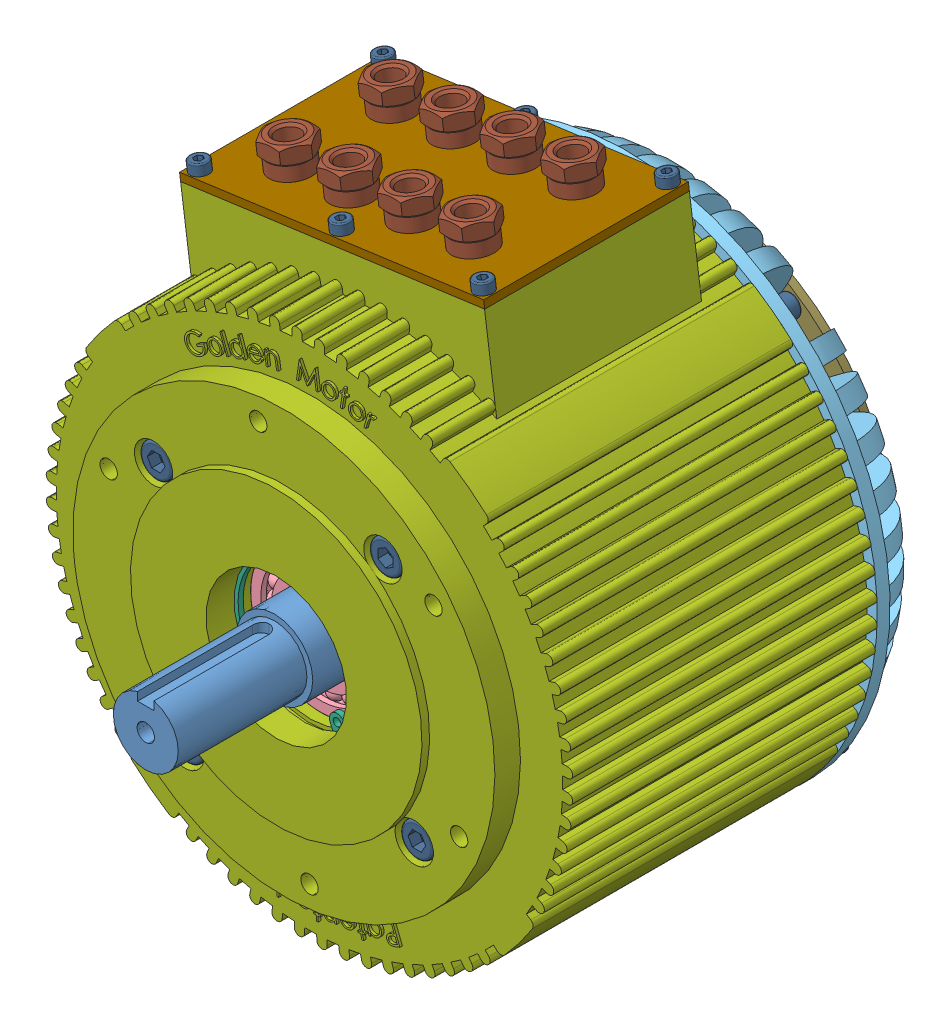
SolidWorks assembly (外形图）风冷图, configuration 默认. Lengths in mm.
Overall size (233.48 249.83 219).
48 component instances, 13 part files, 43 mates.
Components (placement in the parent):
- 轴-1: 轴 [默认] at (4.5506 0 -103.5) size (35 35 206.3)
- Hexagon socket button head screws GB-1: Hexagon socket button head screws GB [GB_SOCKET_TYPE7 M4X8-N] at (-6.919 -27.7209 -32.7) x (0 0 1) z (0.923728 0.383049 0) size (10.2 7.6 7.6)
- Hexagon socket button head screws GB-2: Hexagon socket button head screws GB [GB_SOCKET_TYPE7 M4X8-N] at (-6.9409 27.7118 -16.3) x (0 0 -1) z (1 0 0) size (10.2 7.6 7.6)
- Circlips for shaft--Type A large GB-1: Circlips for shaft--Type A large GB [GB_CONNECTING_PIECE_RING_RRA 30] at (4.3214 0.9013 -39.6) x (0.969151 0.246466 0) z (0 0 1) size (33.5 36.57 1.2)
- Deep groove ball bearings GB-1: Deep groove ball bearings GB [Rolling bearings 16006 GB 276-94] at (4.5506 0 30) x (0 0 1) z (0.923728 0.383049 0) size (9 55 55)
- Deep groove ball bearings GB-2: Deep groove ball bearings GB [Rolling bearings 6205 GB 276-94] at (4.5506 0 -72) x (0 0 1) z (-1 0 0) size (15 52 52)
- 盖-1: 盖 [默认] at (4.5506 0 -61) x (0.135368 -0.990795 0) z (0 0 -1) size (206 206 49.2)
- Circlips for holes--Type A GB-1: Circlips for holes--Type A GB [GB_CONNECTING_PIECE_RING_RRH 52] at (5.0102 -1.1085 -81.5) x (0.923728 0.383049 0) z (0 0 -1) size (56.2 54.06 2)
- 机壳-1: 机壳 [默认] at (4.5506 0 51.8) x (-0.990795 -0.135368 0) z (0 0 -1) size (206 217 132)
- 风页-1: 风页 [默认] at (4.5506 0 -82.4) x (0 0 1) z (-1 0 0) size (25.28 108.45 96.5)
- 出线板-1: 出线板 [默认] at (-6.2623 113.5818 -4.2972) x (0.990795 0.135368 0) z (-0.135368 0.990795 0) size (120 80 3)
- Hexagon socket head cap screws GB-1: Hexagon socket head cap screws GB [GB_FASTENER_SCREWS_HSHCS M5X16-N] at (-73.4886 59.2781 -90.2) x (0 0 1) z (-1 0 0) size (21 8.5 8.5)
- Hexagon socket head cap screws GB-2: Hexagon socket head cap screws GB [GB_FASTENER_SCREWS_HSHCS M8X16-N] at (43.2628 50.9643 -93.2) x (0 0 1) z (-1 0 0) size (24 13 13)
- Hexagon socket head cap screws GB-3: Hexagon socket head cap screws GB [GB_FASTENER_SCREWS_HSHCS M8X20-N] at (-46.4138 38.7122 47.8) x (0 0 -1) z (1 0 0) size (28 13 13)
- Prevailing torque type 1 with fine pitch GB-1: Prevailing torque type 1 with fine pitch GB [GB_HEXAGON_TYPE11 M10X1-N] at (-47.654 116.1578 -45.7) x (0.497865 0.068021 -0.864583) z (0.135368 -0.990795 0) size (18.48 16 11.9)
- Hexagon socket head cap screws GB-4: Hexagon socket head cap screws GB [GB_FASTENER_SCREWS_HSHCS M3X10-N] at (-4.9252 69.3557 -116.2) x (0 0 1) z (0.380828 0.924646 0) size (13 5.5 5.5)
- Circlips for shaft--Type A large GB-3: Circlips for shaft--Type A large GB [GB_CONNECTING_PIECE_RING_RRA 14] at (4.5506 0.47 -100.4) size (15.7 18.22 1)
- Hexagon socket head cap screws GB-5: Hexagon socket head cap screws GB [GB_FASTENER_SCREWS_HSHCS M8X20-N] at (43.2628 50.9643 47.8) x (0 0 -1) z (0 -1 0) size (28 13 13)
- Hexagon socket head cap screws GB-6: Hexagon socket head cap screws GB [GB_FASTENER_SCREWS_HSHCS M8X20-N] at (55.5149 -38.7122 47.8) x (0 0 -1) z (-1 0 0) size (28 13 13)
- Hexagon socket head cap screws GB-7: Hexagon socket head cap screws GB [GB_FASTENER_SCREWS_HSHCS M8X20-N] at (-34.1616 -50.9643 47.8) x (0 0 -1) z (0 1 0) size (28 13 13)
- Hexagon socket head cap screws GB-8: Hexagon socket head cap screws GB [GB_FASTENER_SCREWS_HSHCS M8X16-N] at (55.5149 -38.7122 -93.2) x (0 0 1) z (0 1 0) size (24 13 13)
- Hexagon socket head cap screws GB-9: Hexagon socket head cap screws GB [GB_FASTENER_SCREWS_HSHCS M8X16-N] at (-34.1616 -50.9643 -93.2) x (0 0 1) z (1 0 0) size (24 13 13)
- Hexagon socket head cap screws GB-10: Hexagon socket head cap screws GB [GB_FASTENER_SCREWS_HSHCS M8X16-N] at (-46.4138 38.7122 -93.2) x (0 0 1) z (0 -1 0) size (24 13 13)
- Hexagon socket head cap screws GB-11: Hexagon socket head cap screws GB [GB_FASTENER_SCREWS_HSHCS M5X16-N] at (63.8287 78.0391 -90.2) x (0 0 1) z (0 1 0) size (21 8.5 8.5)
- Hexagon socket head cap screws GB-12: Hexagon socket head cap screws GB [GB_FASTENER_SCREWS_HSHCS M5X16-N] at (82.5897 -59.2781 -90.2) x (0 0 1) z (1 0 0) size (21 8.5 8.5)
- Hexagon socket head cap screws GB-13: Hexagon socket head cap screws GB [GB_FASTENER_SCREWS_HSHCS M5X16-N] at (-54.7275 -78.0391 -90.2) x (0 0 1) z (0 -1 0) size (21 8.5 8.5)
- Circlips for holes--Type A GB-2: Circlips for holes--Type A GB [GB_CONNECTING_PIECE_RING_RRH 55] at (4.5506 1.2 40.6) size (59.2 56.95 2)
- Prevailing torque type 1 with fine pitch GB-2: Prevailing torque type 1 with fine pitch GB [GB_HEXAGON_TYPE11 M10X1-N] at (-47.654 116.1578 -5.7) x (0.497865 0.068021 -0.864583) z (0.135368 -0.990795 0) size (18.48 16 11.9)
- Prevailing torque type 1 with fine pitch GB-3: Prevailing torque type 1 with fine pitch GB [GB_HEXAGON_TYPE11 M10X1-N] at (-23.8749 119.4066 -45.7) x (0.497865 0.068021 -0.864583) z (0.135368 -0.990795 0) size (18.48 16 11.9)
- Prevailing torque type 1 with fine pitch GB-4: Prevailing torque type 1 with fine pitch GB [GB_HEXAGON_TYPE11 M10X1-N] at (-23.8749 119.4066 -5.7) x (0.497865 0.068021 -0.864583) z (0.135368 -0.990795 0) size (18.48 16 11.9)
- Prevailing torque type 1 with fine pitch GB-5: Prevailing torque type 1 with fine pitch GB [GB_HEXAGON_TYPE11 M10X1-N] at (-0.0958 122.6554 -45.7) x (0.497865 0.068021 -0.864583) z (0.135368 -0.990795 0) size (18.48 16 11.9)
- Prevailing torque type 1 with fine pitch GB-6: Prevailing torque type 1 with fine pitch GB [GB_HEXAGON_TYPE11 M10X1-N] at (-0.0958 122.6554 -5.7) x (0.497865 0.068021 -0.864583) z (0.135368 -0.990795 0) size (18.48 16 11.9)
- Prevailing torque type 1 with fine pitch GB-7: Prevailing torque type 1 with fine pitch GB [GB_HEXAGON_TYPE11 M10X1-N] at (23.6833 125.9043 -45.7) x (0.497865 0.068021 -0.864583) z (0.135368 -0.990795 0) size (18.48 16 11.9)
- Prevailing torque type 1 with fine pitch GB-8: Prevailing torque type 1 with fine pitch GB [GB_HEXAGON_TYPE11 M10X1-N] at (23.6833 125.9043 -5.7) x (0.497865 0.068021 -0.864583) z (0.135368 -0.990795 0) size (18.48 16 11.9)
- Hexagon socket head cap screws GB-14: Hexagon socket head cap screws GB [GB_FASTENER_SCREWS_HSHCS M4X10-N] at (-67.3135 112.3056 10.3) x (0.135368 -0.990795 0) z (0 0 1) size (14 7 7)
- Hexagon socket head cap screws GB-15: Hexagon socket head cap screws GB [GB_FASTENER_SCREWS_HSHCS M4X10-N] at (-67.3135 112.3056 -61.7) x (0.135368 -0.990795 0) z (0 0 1) size (14 7 7)
- Hexagon socket head cap screws GB-16: Hexagon socket head cap screws GB [GB_FASTENER_SCREWS_HSHCS M4X10-N] at (-11.829 119.8862 10.3) x (0.135368 -0.990795 0) z (0 0 1) size (14 7 7)
- Hexagon socket head cap screws GB-17: Hexagon socket head cap screws GB [GB_FASTENER_SCREWS_HSHCS M4X10-N] at (-11.829 119.8862 -61.7) x (0.135368 -0.990795 0) z (0 0 1) size (14 7 7)
- Hexagon socket head cap screws GB-18: Hexagon socket head cap screws GB [GB_FASTENER_SCREWS_HSHCS M4X10-N] at (43.6556 127.4669 10.3) x (0.135368 -0.990795 0) z (0 0 1) size (14 7 7)
- Hexagon socket head cap screws GB-19: Hexagon socket head cap screws GB [GB_FASTENER_SCREWS_HSHCS M4X10-N] at (43.6556 127.4669 -61.7) x (0.135368 -0.990795 0) z (0 0 1) size (14 7 7)
- 风页盖板-1: 风页盖板 [默认] at (4.5506 0 -113.2) x (0.990795 0.135368 0) z (0 0 1) size (150 150 3)
- Hexagon socket head cap screws GB-20: Hexagon socket head cap screws GB [GB_FASTENER_SCREWS_HSHCS M3X10-N] at (-64.8051 -9.4758 -116.2) x (0 0 1) z (-0.924646 0.380828 0) size (13 5.5 5.5)
- Hexagon socket head cap screws GB-21: Hexagon socket head cap screws GB [GB_FASTENER_SCREWS_HSHCS M3X10-N] at (14.0264 -69.3557 -116.2) x (0 0 1) z (-0.380828 -0.924646 0) size (13 5.5 5.5)
- Hexagon socket head cap screws GB-22: Hexagon socket head cap screws GB [GB_FASTENER_SCREWS_HSHCS M3X10-N] at (73.9063 9.4758 -116.2) x (0 0 1) z (0.924646 -0.380828 0) size (13 5.5 5.5)
- 端子-1: 端子 [默认] at (-63.2107 -47.0601 -82.2) x (-0.923728 -0.383049 0) z (0 0 -1) size (12 12 4)
- 端子-2: 端子 [默认] at (-73.3509 27.1588 -82.2) x (-0.852847 0.522161 0) z (0 0 -1) size (12 12 4)
- 端子-3: 端子 [默认] at (-77.9307 1.7567 -82.2) x (-0.972462 0.233061 0) z (0 0 -1) size (12 12 4)
- 端子-4: 端子 [默认] at (-74.4366 -23.8174 -82.2) x (-0.996886 -0.078854 0) z (0 0 -1) size (12 12 4)
Mates (geometry in assembly coordinates):
- 同心8: concentric anti-aligned: circle of 轴-1; circle of Circlips for shaft--Type A large GB-1
- 重合6: coincident anti-aligned: circle of 轴-1; plane of Circlips for shaft--Type A large GB-1 through (4.5506 0 -40.8) normal (0 0 -1)
- 同心11: concentric anti-aligned: circle of 轴-1; circle of Deep groove ball bearings GB-2
- 重合10: coincident aligned: circle of 轴-1; plane of Deep groove ball bearings GB-2 through (4.5506 12.5 -64.5) normal (0 0 1)
- 同心12: concentric aligned: circle of 轴-1; circle of Deep groove ball bearings GB-1
- 重合11: coincident anti-aligned: plane of 轴-1 through (4.5506 0 25.5) normal (0 0 1); plane of Deep groove ball bearings GB-1 through (15.0844 -25.4025 25.5) normal (0 0 -1)
- 重合13: coincident aligned: plane of Deep groove ball bearings GB-2 through (4.5506 26 -79.5) normal (0 0 -1); circle of 盖-1
- 同心15: concentric aligned: circle of 轴-1; circle of Circlips for holes--Type A GB-1
- 重合14: coincident anti-aligned: plane of 盖-1 through (4.5506 0 -79.5) normal (0 0 -1); plane of Circlips for holes--Type A GB-1 through (5.0102 -1.1085 -79.5) normal (0 0 1)
- 同心25: concentric aligned: circle of 盖-1; circle of 机壳-1
- 重合32: coincident anti-aligned: circle of 盖-1; plane of 机壳-1 through (4.5506 0 -80.2) normal (0 0 -1)
- 同心27: concentric anti-aligned: circle of 盖-1; circle of 机壳-1
- 同心28: concentric aligned: circle of 轴-1; circle of 风页-1
- 重合35: coincident anti-aligned: circle of 轴-1; plane of 风页-1 through (4.5506 7 -100.4) normal (0 0 -1)
- 重合36: coincident anti-aligned: plane of 机壳-1 through (-70.3291 104.8286 14.3) normal (-0.135368 0.990795 0); plane of 出线板-1 through (-70.3291 104.8286 14.3) normal (0.135368 -0.990795 0)
- 重合37: coincident aligned: plane of 机壳-1 through (-40.9541 -110.175 14.3) normal (-0.990795 -0.135368 0); plane of 出线板-1 through (-70.7352 107.801 -65.7) normal (-0.990795 -0.135368 0)
- 重合38: coincident aligned: plane of 机壳-1 through (-40.9541 -110.175 -65.7) normal (0 0 -1); plane of 出线板-1 through (-70.7352 107.801 -65.7) normal (0 0 -1)
- 同心30: concentric anti-aligned: circle of 机壳-1; circle of Hexagon socket head cap screws GB-3
- 重合40: coincident anti-aligned: plane of 机壳-1 through (-51.3677 38.0354 39.8) normal (0 0 1); circle of Hexagon socket head cap screws GB-3
- 同心31: concentric anti-aligned: circle of 盖-1; circle of Hexagon socket head cap screws GB-2
- 重合41: coincident anti-aligned: plane of 盖-1 through (229.2049 30.6936 -85.2) normal (0 0 -1); circle of Hexagon socket head cap screws GB-2
- 同心32: concentric anti-aligned: circle of 盖-1; circle of Hexagon socket head cap screws GB-1
- 重合42: coincident anti-aligned: plane of 盖-1 through (229.2049 30.6936 -85.2) normal (0 0 -1); circle of Hexagon socket head cap screws GB-1
- 同心33: concentric anti-aligned: circle of 轴-1; circle of Circlips for shaft--Type A large GB-3
- 重合44: coincident aligned: plane of 轴-1 through (4.5506 0 -100.4) normal (0 0 -1); circle of Circlips for shaft--Type A large GB-3
- 同心37: concentric aligned: circle of 机壳-1; circle of Circlips for holes--Type A GB-2
- 重合45: coincident anti-aligned: plane of 机壳-1 through (4.5506 0 38.6) normal (0 0 1); circle of Circlips for holes--Type A GB-2
- 同心38: concentric anti-aligned: circle of 出线板-1; circle of Prevailing torque type 1 with fine pitch GB-1
- 重合46: coincident aligned: plane of 出线板-1 through (-70.7352 107.801 14.3) normal (-0.135368 0.990795 0); circle of Prevailing torque type 1 with fine pitch GB-1
- 同心39: concentric anti-aligned: circle of 出线板-1; circle of Hexagon socket head cap screws GB-14
- 重合47: coincident anti-aligned: plane of 出线板-1 through (-70.7352 107.801 14.3) normal (-0.135368 0.990795 0); circle of Hexagon socket head cap screws GB-14
- 同心40: concentric anti-aligned: circle of 盖-1; circle of 风页盖板-1
- 重合48: coincident anti-aligned: plane of 盖-1 through (4.5506 0 -110.2) normal (0 0 -1); circle of 风页盖板-1
- 同心41: concentric anti-aligned: circle of 盖-1; circle of 风页盖板-1
- 同心45: concentric aligned: circle of Hexagon socket head cap screws GB-4; circle of 风页盖板-1
- 重合49: coincident anti-aligned: circle of Hexagon socket head cap screws GB-4; plane of 风页盖板-1 through (4.5506 0 -113.2) normal (0 0 -1)
- 重合52: coincident anti-aligned: plane of 端子-1 through (-63.2107 -47.0601 -82.2) normal (0 0 1); circle of 盖-1
- 同心46: concentric aligned: circle of 盖-1; circle of 端子-1
- 局部圆周阵列7: unknown: line of 盖-1 through (4.5506 0 -85.2) axis (0 0 -1)
- 局部圆周阵列8: unknown: line of 盖-1 through (4.5506 0 -85.2) axis (0 0 -1)
- 局部线性阵列2: unknown: line of 出线板-1 through (-70.7352 107.801 14.3) axis (0.990795 0.135368 0); line of 出线板-1 through (-70.7352 107.801 -65.7) axis (0 0 1)
- 局部圆周阵列9: unknown: line of 风页盖板-1 through (4.5506 0 -113.2) axis (0 0 1)
- 局部圆周阵列10: unknown: line of 风页盖板-1 through (4.5506 0 -113.2) axis (0 0 1)
